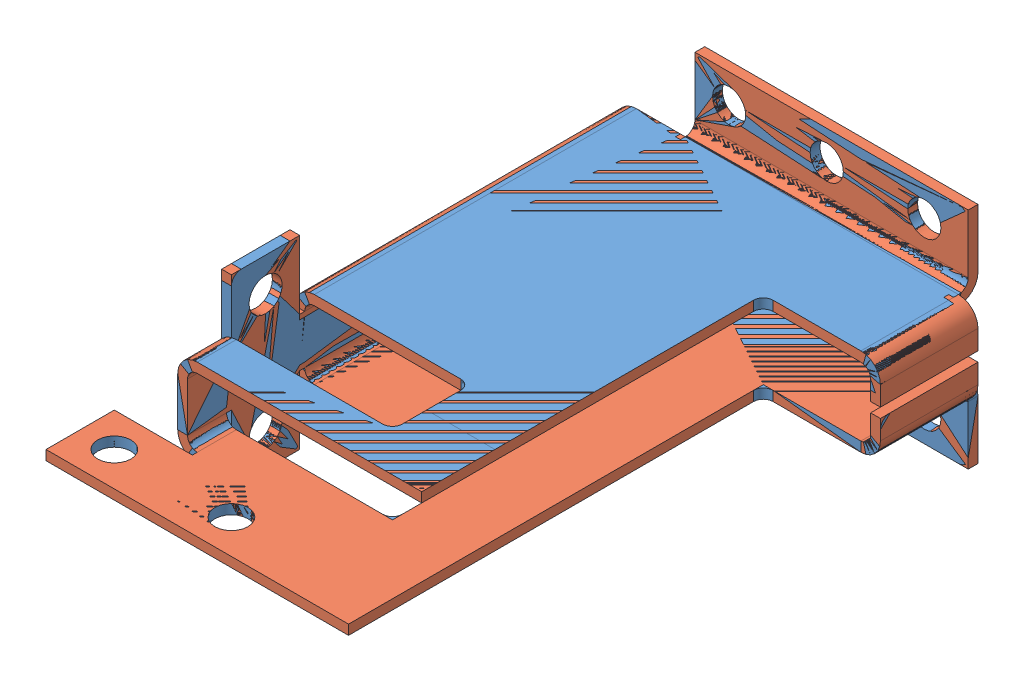
SolidWorks assembly HPPM_OS_Cablerun_Vergleich, configuration Standard. Lengths in mm.
Overall size (43 23 54.5).
3 component instances, 3 part files, 6 mates.
Components (placement in the parent):
- HPPM_OS_Cablerun-1: HPPM_OS_Cablerun [Standard] at (-20.8043 -0.5371 65.5) (suppressed, hidden)
- HPPM_OS_Cablerun_Blech-1: HPPM_OS_Cablerun_Blech [Standard] at (-22.8043 2.9629 57.1169) x (0 -1 0) z (-1 0 0) size (23 54.5 43)
- HPPM_OS_Cablerun_NEU-1: HPPM_OS_Cablerun_NEU [Standard] at (-20.8043 -0.5371 57.1169) size (43 23 54.5)
Mates (geometry in assembly coordinates):
- Deckungsgleich1: coincident aligned: plane of HPPM_OS_Cablerun-1 through (12.1957 4.9629 63.5) normal (0 0 -1); plane of HPPM_OS_Cablerun_Blech-1 through (-22.8043 2.9629 63.5) normal (0 0 -1)
- Deckungsgleich2: coincident aligned: plane of HPPM_OS_Cablerun-1 through (-22.8043 1.9629 65.5) normal (-1 0 0); plane of HPPM_OS_Cablerun_Blech-1 through (-22.8043 2.9629 66.5) normal (-1 0 0)
- Deckungsgleich3: coincident aligned: plane of HPPM_OS_Cablerun-1 through (12.1957 3.9629 65.5) normal (0 1 0); plane of HPPM_OS_Cablerun_Blech-1 through (-22.8043 3.9629 66.5) normal (0 1 0)
- Deckungsgleich4: coincident aligned: plane of HPPM_OS_Cablerun_Blech-1 through (-22.8043 2.9629 55.1169) normal (0 0 -1); plane of HPPM_OS_Cablerun_NEU-1 through (12.1957 4.9629 55.1169) normal (0 0 -1)
- Deckungsgleich5: coincident aligned: plane of HPPM_OS_Cablerun_Blech-1 through (-22.8043 -4.0371 57.1169) normal (0 1 0); plane of HPPM_OS_Cablerun_NEU-1 through (12.1957 -4.0371 57.1169) normal (0 1 0)
- Deckungsgleich6: coincident aligned: plane of HPPM_OS_Cablerun_Blech-1 through (-21.8043 2.9629 57.1169) normal (1 0 0); plane of HPPM_OS_Cablerun_NEU-1 through (-21.8043 -3.0371 57.1169) normal (1 0 0)
